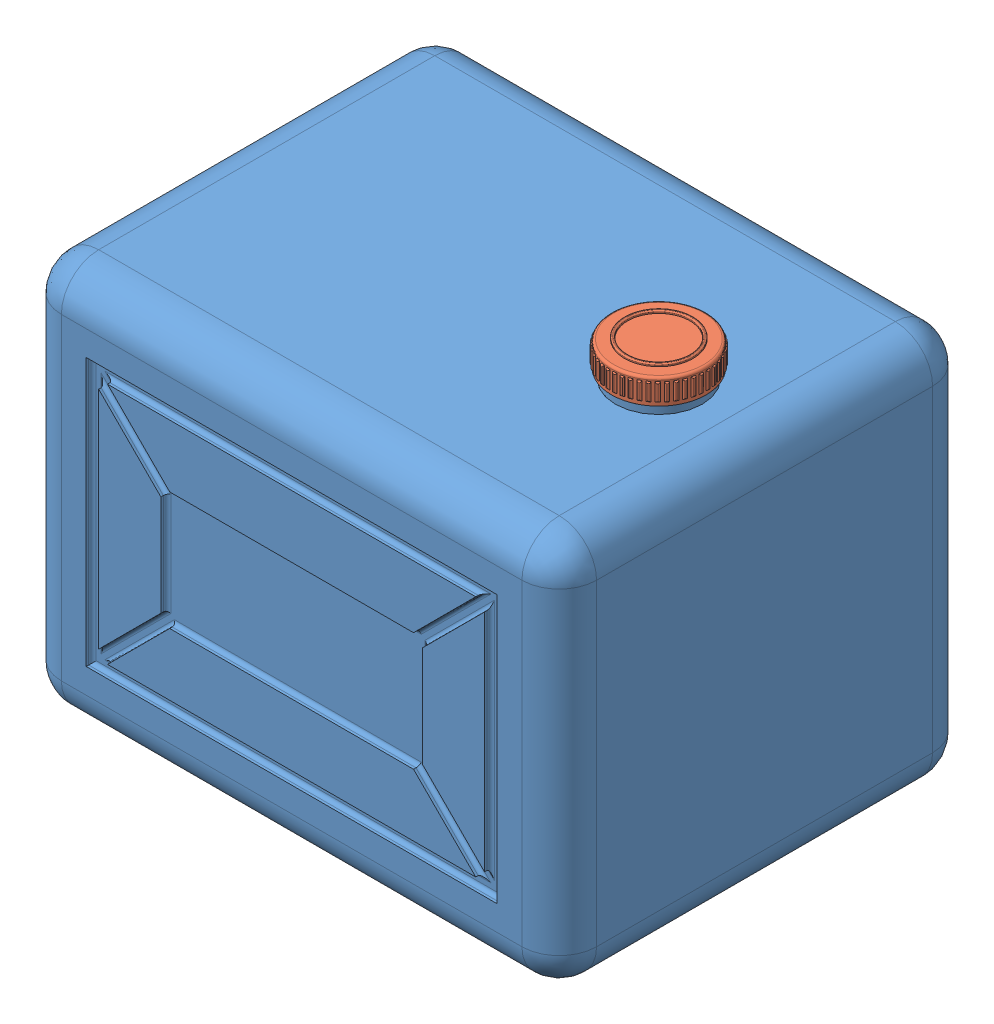
SolidWorks assembly water_tank, configuration Default. Lengths in mm.
Overall size (430 360 330.5).
2 component instances, 2 part files, 2 mates.
Components (placement in the parent):
- tank-1: tank [Default] at (-9.2906 -176.8602 14.9078) size (430 355 330.5)
- tank_cap-2: tank_cap [Default] at (120.7094 146.1398 14.9078) x (-0.244108 0 -0.969748) z (0.969748 0 -0.244108) size (77.99 22 77.94)
Mates (geometry in assembly coordinates):
- Concentric1: concentric aligned: circle of Tank-1; circle of Tutup tank-2
- Coincident4: coincident anti-aligned: plane of Tank-1 through (120.7094 163.1398 14.9078) normal (0 1 0); plane of Tutup tank-2 through (120.7094 163.1398 14.9078) normal (0 -1 0)
